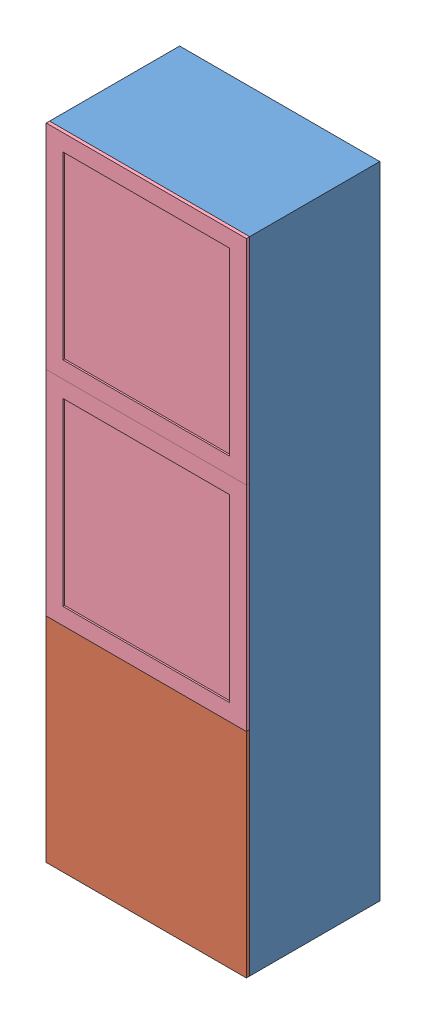
SolidWorks assembly Schrank-R, configuration Standard. Lengths in mm.
Overall size (600 1920 400).
6 component instances, 4 part files, 14 mates.
Components (placement in the parent):
- Schrank-Korpus-1: Schrank-Korpus [Standard] at (68.177 -29.4401 1725) size (600 1920 390)
- Türe-1: Türe [Standard] at (68.177 -669.4401 2115) size (600 640 10)
- Regalbrett-1: Regalbrett [Standard] at (68.177 -354.4401 2095) x (1 0 0) z (0 1 0) size (560 360 10)
- Regalbrett-2: Regalbrett [Standard] at (68.177 285.5599 2095) x (1 0 0) z (0 1 0) size (560 360 10)
- SINDVIK-Vitrinentüre-1: SINDVIK-Vitrinentüre [Standard] at (68.177 -29.4401 2115) size (600 640 10)
- SINDVIK-Vitrinentüre-2: SINDVIK-Vitrinentüre [Standard] at (68.177 610.5599 2115) size (600 640 10)
Mates (geometry in assembly coordinates):
- Deckungsgleich1: coincident anti-aligned: plane of Schrank-Korpus-1 through (68.177 -29.4401 1735) normal (0 0 1); plane of Regalbrett-2 through (68.177 285.5599 1735) normal (0 0 -1)
- Deckungsgleich2: coincident anti-aligned: plane of Schrank-Korpus-1 through (-211.823 910.5599 2115) normal (1 0 0); plane of Regalbrett-2 through (-211.823 290.5599 1735) normal (-1 0 0)
- Deckungsgleich3: coincident anti-aligned: plane of Schrank-Korpus-1 through (68.177 -29.4401 1735) normal (0 0 1); plane of Regalbrett-1 through (68.177 -354.4401 1735) normal (0 0 -1)
- Deckungsgleich4: coincident anti-aligned: plane of Schrank-Korpus-1 through (-211.823 910.5599 2115) normal (1 0 0); plane of Regalbrett-1 through (-211.823 -349.4401 1735) normal (-1 0 0)
- Deckungsgleich5: coincident aligned: plane of Schrank-Korpus-1 through (368.177 -989.4401 1735) normal (1 0 0); plane of Türe-1 through (368.177 -989.4401 2125) normal (1 0 0)
- Deckungsgleich6: coincident aligned: plane of Schrank-Korpus-1 through (-231.823 -989.4401 1735) normal (0 -1 0); plane of Türe-1 through (-231.823 -989.4401 2125) normal (0 -1 0)
- Deckungsgleich11: coincident anti-aligned: plane of Schrank-Korpus-1 through (68.177 -29.4401 2115) normal (0 0 1); plane of Türe-1 through (68.177 -669.4401 2115) normal (0 0 -1)
- Deckungsgleich12: coincident aligned: plane of Türe-1 through (-231.823 -349.4401 2125) normal (0 1 0); plane of Regalbrett-1 through (-211.823 -349.4401 1735) normal (0 1 0)
- Deckungsgleich13: coincident anti-aligned: plane of Schrank-Korpus-1 through (68.177 -29.4401 2115) normal (0 0 1); plane of SINDVIK-Vitrinentüre-1 through (68.177 -29.4401 2115) normal (0 0 -1)
- Deckungsgleich14: coincident anti-aligned: plane of Schrank-Korpus-1 through (68.177 -29.4401 2115) normal (0 0 1); plane of SINDVIK-Vitrinentüre-2 through (68.177 610.5599 2115) normal (0 0 -1)
- Deckungsgleich15: coincident aligned: plane of Schrank-Korpus-1 through (-231.823 -989.4401 1735) normal (-1 0 0); plane of SINDVIK-Vitrinentüre-1 through (-231.823 -349.4401 2125) normal (-1 0 0)
- Deckungsgleich16: coincident aligned: plane of Schrank-Korpus-1 through (-231.823 -989.4401 1735) normal (-1 0 0); plane of SINDVIK-Vitrinentüre-2 through (-231.823 290.5599 2125) normal (-1 0 0)
- Deckungsgleich17: coincident anti-aligned: plane of Türe-1 through (-231.823 -349.4401 2125) normal (0 1 0); plane of SINDVIK-Vitrinentüre-1 through (-231.823 -349.4401 2125) normal (0 -1 0)
- Deckungsgleich18: coincident anti-aligned: plane of SINDVIK-Vitrinentüre-1 through (-231.823 290.5599 2125) normal (0 1 0); plane of SINDVIK-Vitrinentüre-2 through (-231.823 290.5599 2125) normal (0 -1 0)
